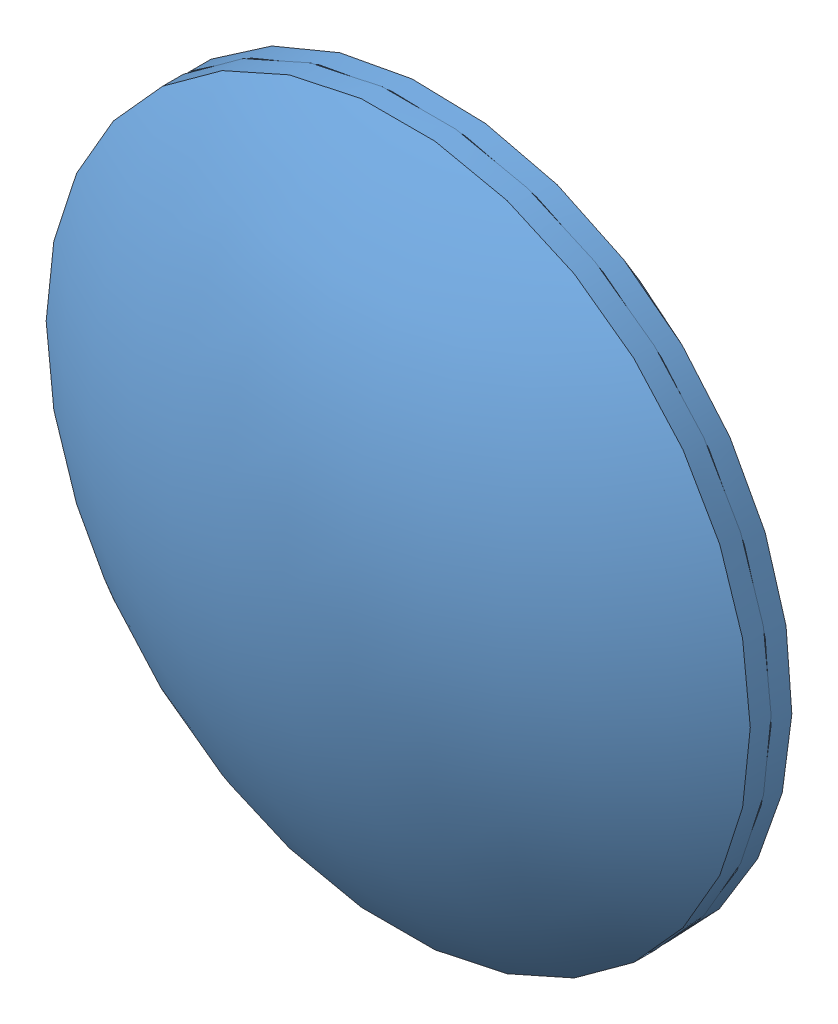
SolidWorks assembly 50.2 mm lense, configuration Default. Lengths in mm.
Overall size (66.38 66.38 19.74).
2 component instances, 1 part files, 1 mates.
Components (placement in the parent):
- 50.2 mm lens half-1: 50.2 mm lens half [Default] at (29.3355 29.4432 29.2096) size (50.8 50.8 9.87)
- 50.2 mm lens half-2: 50.2 mm lens half [Default] at (29.3355 29.4432 94.9456) x (-0.923728 -0.383049 0) z (0 0 -1) size (50.8 50.8 9.87)
Mates (geometry in assembly coordinates):
- Coincident1: coincident anti-aligned: circle of 50.2 mm lens half-1; circle of 50.2 mm lens half-2
